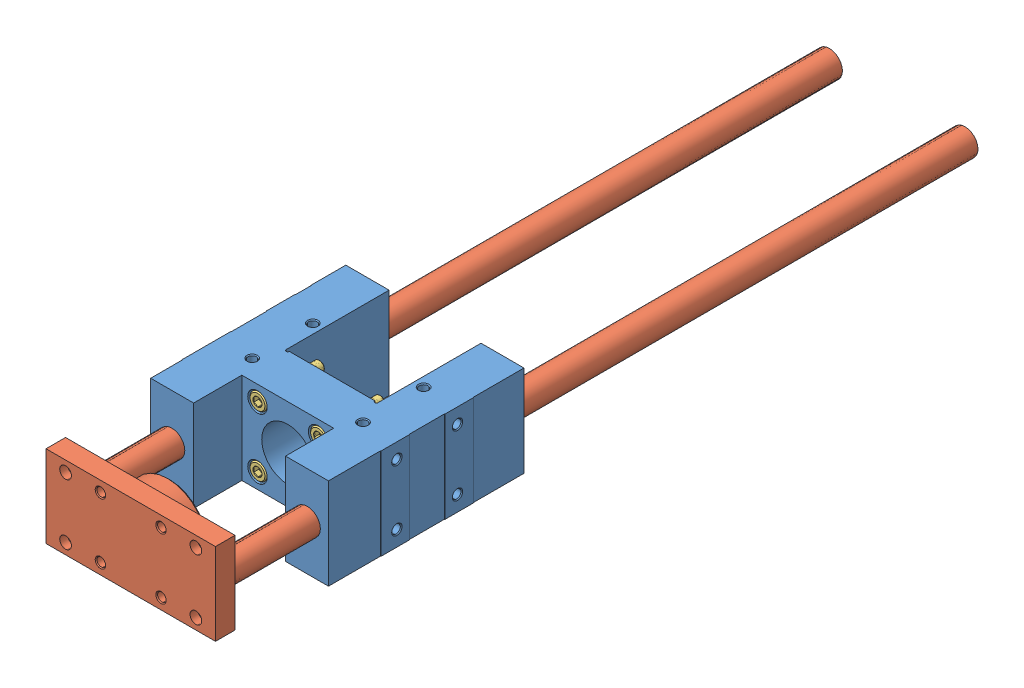
SolidWorks assembly 150292 FENG-50-400-KF---(asm_0), configuration Default. Lengths in mm.
Overall size (137 70 588).
6 component instances, 3 part files, 14 mates.
Components (placement in the parent):
- 150292 FENG-50-KF---(GK)-1: 150292 FENG-50-KF---(GK) [Default] at origin size (137 70 150)
- 150292 FENG-50-400-KF---(JS)-1: 150292 FENG-50-400-KF---(JS) [Default] at (0 0 65.4893) size (130 63 588)
- DIN-912 - M8x40(F)-1: DIN-912 - M8x40(F) [Default] at (23.25 23.25 26) x (1 0 0) z (0 -1 0) size (13 48.35 13)
- DIN-912 - M8x40(F)-2: DIN-912 - M8x40(F) [Default] at (-23.25 23.25 26) x (1 0 0) z (0 -1 0) size (13 48.35 13)
- DIN-912 - M8x40(F)-3: DIN-912 - M8x40(F) [Default] at (23.25 -23.25 26) x (1 0 0) z (0 -1 0) size (13 48.35 13)
- DIN-912 - M8x40(F)-4: DIN-912 - M8x40(F) [Default] at (-23.25 -23.25 26) x (1 0 0) z (0 -1 0) size (13 48.35 13)
Mates (geometry in assembly coordinates):
- Coincident1: coincident aligned: line of 150292 FENG-50-KF---(GK)-1 through (0 0 80.9) axis (0 0 -1); line of 150292 FENG-50-400-KF---(JS)-1 through (0 0 146.3893) axis (0 0 -1)
- Angle3: planar angle = 0 rad aligned: plane of 150292 FENG-50-400-KF---(JS)-1 through (0 0 65.4893) normal (1 0 0); plane of 150292 FENG-50-KF---(GK)-1 through (0 0 0) normal (1 0 0)
- Distance2: distance = 0 mm aligned: plane of 150292 FENG-50-KF---(GK)-1 through (0 0 26) normal (0 0 1); plane of DIN-912 - M8x40(F)-1 through (23.25 23.25 26) normal (0 0 1)
- Coincident2: coincident aligned: line of 150292 FENG-50-KF---(GK)-1 through (23.25 23.25 80.9) axis (0 0 -1); line of DIN-912 - M8x40(F)-1 through (23.25 23.25 76) axis (0 0 -1)
- Angle6: planar angle = 0 rad aligned: plane of DIN-912 - M8x40(F)-1 through (23.25 23.25 26) normal (1 0 0); plane of 150292 FENG-50-KF---(GK)-1 through (23.25 0 0) normal (1 0 0)
- Distance4: distance = 0 mm aligned: plane of 150292 FENG-50-KF---(GK)-1 through (0 0 26) normal (0 0 1); plane of DIN-912 - M8x40(F)-2 through (-23.25 23.25 26) normal (0 0 1)
- Coincident3: coincident aligned: line of 150292 FENG-50-KF---(GK)-1 through (-23.25 23.25 80.9) axis (0 0 -1); line of DIN-912 - M8x40(F)-2 through (-23.25 23.25 76) axis (0 0 -1)
- Angle9: planar angle = 0 rad aligned: plane of DIN-912 - M8x40(F)-2 through (-23.25 23.25 26) normal (1 0 0); plane of 150292 FENG-50-KF---(GK)-1 through (-23.25 0 0) normal (1 0 0)
- Distance6: distance = 0 mm aligned: plane of 150292 FENG-50-KF---(GK)-1 through (0 0 26) normal (0 0 1); plane of DIN-912 - M8x40(F)-3 through (23.25 -23.25 26) normal (0 0 1)
- Coincident4: coincident aligned: line of 150292 FENG-50-KF---(GK)-1 through (23.25 -23.25 80.9) axis (0 0 -1); line of DIN-912 - M8x40(F)-3 through (23.25 -23.25 76) axis (0 0 -1)
- Angle12: planar angle = 0 rad aligned: plane of DIN-912 - M8x40(F)-3 through (23.25 -23.25 26) normal (1 0 0); plane of 150292 FENG-50-KF---(GK)-1 through (23.25 0 0) normal (1 0 0)
- Distance8: distance = 0 mm aligned: plane of 150292 FENG-50-KF---(GK)-1 through (0 0 26) normal (0 0 1); plane of DIN-912 - M8x40(F)-4 through (-23.25 -23.25 26) normal (0 0 1)
- Coincident5: coincident aligned: line of 150292 FENG-50-KF---(GK)-1 through (-23.25 -23.25 80.9) axis (0 0 -1); line of DIN-912 - M8x40(F)-4 through (-23.25 -23.25 76) axis (0 0 -1)
- Angle15: planar angle = 0 rad aligned: plane of DIN-912 - M8x40(F)-4 through (-23.25 -23.25 26) normal (1 0 0); plane of 150292 FENG-50-KF---(GK)-1 through (-23.25 0 0) normal (1 0 0)
